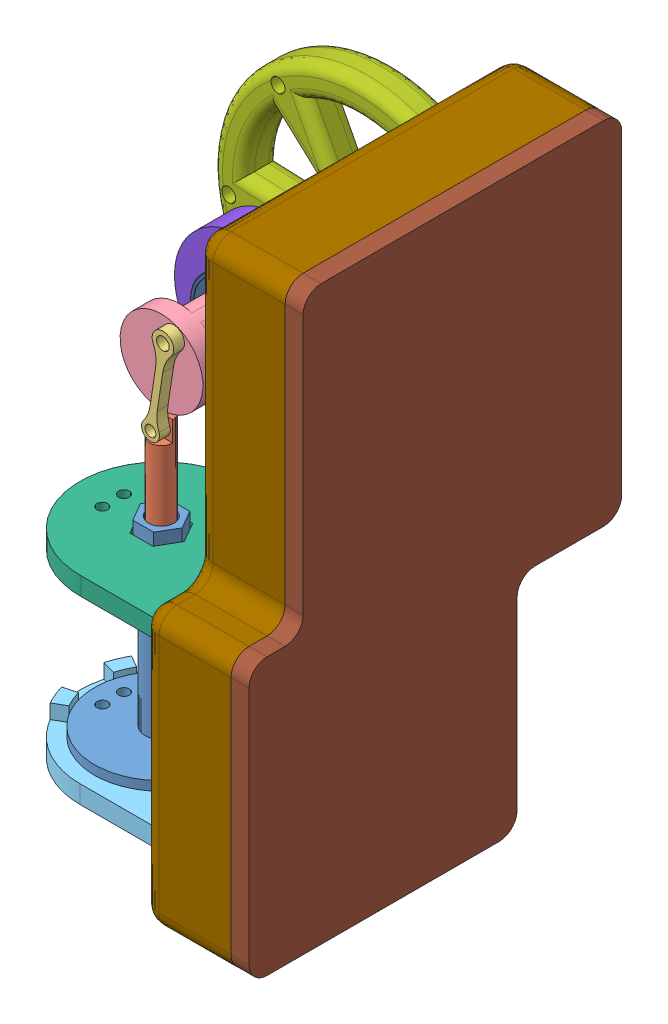
SolidWorks assembly 2pisengine, configuration Default. Lengths in mm.
Overall size (108.68 162.99 107.76).
15 component instances, 13 part files, 44 mates.
Components (placement in the parent):
- actuater-1: actuater [Default] at origin size (37.1 77.79 37.1) (flexible)
  - Spool_V1-1: Spool_V1 [Default] at (35.0022 -0.1462 27.5826) size (37.1 53.12 37.1)
  - rod2-1: rod2 [Default] at (35.0022 77.6418 27.5826) x (-1 0 0) z (0 -1 0) size (6.35 6.35 45.12)
- linkage-2: linkage [Default] at (38.4493 97.5834 30.5826) x (-0.149874 -0.988705 0) z (0.988705 -0.149874 0) size (28.5 3 6)
- pin-2: pin [Default] at (35.0022 74.8431 24.9704) x (0.997592 0.06936 0) z (0.06936 -0.997592 0) size (2.5 16 2.5) (hidden)
- spinner-1: spinner [Default] at (35.0682 90 -77.4174) x (0.407215 0.913332 0) z (0 0 1) size (23 23 64.21)
- base-1: base [Default] at (35.0022 -5.1462 27.5826) x (0 1 0) z (0 0 1) size (9 48.18 45.14)
- base2-1: base2 [Default] at (35.0022 49.9738 27.5826) x (0 -1 0) z (0.266317 0 0.963886) size (52.64 53.27 51.14)
- holder-2: holder [Default] at (35.0682 90 -36.6259) x (0 0 1) z (-0.462866 0.886428 0) size (10.59 80.54 80.54)
- holder2-1: holder2 [Default] at (35.0682 90 5.0146) x (0 0 -1) z (1 0 0) size (10 37.96 44.48)
- Part2-1: Part2 [Default] at (63.5682 -5.1462 50.1505) x (0 -1 0) z (1 0 0) size (158.81 103.42 25)
- 608RS-1: 608RS [Default] at (35.0682 90 -5.0854) x (0.988989 0.14799 0) z (0 0 1) size (22 22 7)
- 608RS-2: 608RS [Default] at (35.0682 90 1.7146) x (0.99964 0.026848 0) z (0 0 1) size (22 22 7)
- bottomlid-1: bottomlid [Default] at (114.8906 -3.1844 28.8479) x (0 -1 0) z (1 0 0)
- Part6^engine-1: Part6^engine [Default] at (83.5682 -5.1462 50.1505) x (0 -1 0) z (1 0 0) size (158.81 103.42 103.17)
Mates (geometry in assembly coordinates):
- Parallel2: parallel anti-aligned: plane of actuater-1/rod-1 through (35.0022 77.6418 27.5826) normal (0 0 1); plane of linkage-2 through (48.2867 89.0848 27.5826) normal (0 0 -1)
- Concentric2: concentric anti-aligned: circle of actuater-1/rod-1; circle of linkage-2
- Coincident5: coincident anti-aligned: plane of actuater-1/rod-1 through (35.0022 77.6418 27.5826) normal (0 0 1); plane of linkage-2 through (48.2867 89.0848 27.5826) normal (0 0 -1)
- Coincident10: coincident aligned: plane of actuater-1/rod-1 through (35.0022 77.6418 27.5826) normal (0 0 1); plane of spinner-1 through (35.0682 90 27.5826) normal (0 0 1)
- Perpendicular1: perpendicular: cylinder of actuater-1/Spool_V1-1 through (35.0022 22.4138 27.5826) axis (0 -1 0) radius 4.55; cylinder of spinner-1 through (35.0682 90 22.5826) axis (0 0 -1) radius 5
- Coincident20: coincident: point of spinner-1; plane of assembly
- Concentric6: concentric anti-aligned: cylinder of actuater-1/rod-1 through (35.0022 74.8431 20.5826) axis (0 0 1) radius 1.5; cylinder of pin-2 through (35.0022 74.8431 30.9704) axis (0 0 -1) radius 1.25
- Concentric10: concentric aligned: cylinder of linkage-2 through (38.4493 97.5834 27.5826) axis (0 0 1) radius 1.75; cylinder of spinner-1 through (38.4493 97.5834 -11.6259) axis (0 0 1) radius 1.5
- Coincident23: coincident anti-aligned: plane of actuater-1/Spool_V1-1 through (35.0022 -0.1462 27.5826) normal (0 -1 0); plane of base-1 through (35.0022 -0.1462 27.5826) normal (0 1 0)
- Coincident25: coincident: plane of actuater-1/Spool_V1-1 through (35.0022 44.9738 27.5826) normal (0 1 0); plane of base2-1 through (35.0022 44.9738 27.5826) normal (0 -1 0)
- Concentric13: concentric aligned: circle of actuater-1/Spool_V1-1; circle of base-1
- Parallel5: parallel anti-aligned: line of base2-1 through (58.5682 44.9738 45.1005) axis (0 -1 0); line of basebot-1 through (58.5682 -0.0962 50.1505) axis (0 1 0)
- Parallel6: parallel aligned: line of base2-1 through (58.5682 44.9738 10.0646) axis (0 -1 0); line of basebot-1 through (58.5682 44.9238 5.0146) axis (0 -1 0)
- Parallel7: parallel anti-aligned: plane of base2-1 through (58.5682 81.778 10.0646) normal (1 0 0); plane of basebot-1 through (58.5682 -5.1462 50.1505) normal (-1 0 0)
- Coincident32: coincident anti-aligned: plane of base2-1 through (58.5682 81.778 10.0646) normal (1 0 0); plane of basebot-1 through (58.5682 -5.1462 50.1505) normal (-1 0 0)
- Coincident35: coincident aligned: plane of base-1 through (60.6182 -5.1462 5.0146) normal (0 0 -1); plane of basebot-1 through (58.5682 -5.1462 5.0146) normal (0 0 -1)
- Parallel12: parallel aligned: cylinder of spinner-1 through (35.0682 90 22.5826) axis (0 0 -1) radius 5; line of basebot-1 through (58.5682 108.9805 50.1505) axis (0 0 -1)
- Parallel15: parallel anti-aligned: plane of spinner-1 through (35.0682 90 14.5826) normal (0 0 -1); plane of holder-2 through (35.0682 90 -26.6259) normal (0 0 1)
- Concentric14: concentric aligned: cylinder of spinner-1 through (35.0682 90 13.3741) axis (0 0 -1) radius 4.025; cylinder of holder-2 through (35.0682 90 -26.6259) axis (0 0 -1) radius 4.025
- Coincident43: coincident anti-aligned: plane of spinner-1 through (37.2843 91.1572 -26.6259) normal (0.886428 0.462866 0); plane of holder-2 through (37.2843 91.1572 -26.6259) normal (-0.886428 -0.462866 0)
- Coincident46: coincident anti-aligned: plane of spinner-1 through (35.0682 90 -26.6259) normal (0 0 -1); plane of holder-2 through (35.0682 90 -26.6259) normal (0 0 1)
- Parallel17: parallel anti-aligned: plane of spinner-1 through (35.0682 90 14.5826) normal (0 0 -1); plane of holder2-1 through (35.0682 90 5.0146) normal (0 0 1)
- Concentric15: concentric anti-aligned: cylinder of spinner-1 through (35.0682 90 13.3741) axis (0 0 -1) radius 4.025; cylinder of holder2-1 through (35.0682 90 -4.9854) axis (0 0 1) radius 18.9805
- Coincident49: coincident: point of spinner-1; plane of assembly
- Parallel18: parallel aligned: plane of base2-1 through (35.0022 49.9738 27.5826) normal (0 1 0); plane of holder2-1 through (58.5682 108.9805 -4.9854) normal (0 1 0)
- Coincident51: coincident anti-aligned: line of basebot-1 through (58.5682 71.0195 5.0146) axis (1 0 0); line of holder2-1 through (60.5682 71.0195 5.0146) axis (-1 0 0)
- InPlace1: in place: plane of ? through (63.3682 -5.1462 50.1505) normal (1 0 0); plane of ? through (63.3682 0 0) normal (1 0 0); moOrthogonalPlaneRef_w of ? through (63.3682 -5.1462 50.1505) normal (1 0 0); plane of ? through (63.3682 0 0) normal (0 1 0); plane of ? through (63.3682 -5.1462 50.1505) normal (1 0 0); plane of ? through (63.3682 0 0) normal (0 0 -1); plane of ? through (63.5682 -5.1462 50.1505) normal (1 0 0); unknown of Part2-1
- Coincident52: coincident aligned: plane of ?; plane of Part2-1
- Coincident53: coincident aligned: moOrthogonalPlaneRef_w of basebot-1 through (63.5682 -5.1462 50.1505) normal (0 0 -1); plane of Part2-1 through (63.5682 -5.1462 50.1505) normal (0 0 -1)
- Coincident54: coincident anti-aligned: moOrthogonalPlaneRef_w of basebot-1 through (63.5682 -5.1462 50.1505) normal (0 1 0); plane of Part2-1 through (63.5682 -5.1462 50.1505) normal (0 -1 0)
- Coincident52: coincident anti-aligned: circle of holder2-1; cylinder of 608RS-1 through (35.0682 90 1.9146) axis (0 0 -1) radius 11
- Coincident53: coincident aligned: plane of holder2-1 through (35.0682 90 -4.9854) normal (0 0 -1); plane of 608RS-1 through (35.0682 90 -4.9854) normal (0 0 -1)
- Concentric16: concentric anti-aligned: cylinder of holder2-1 through (35.0682 90 -4.9854) axis (0 0 1) radius 11; cylinder of 608RS-2 through (35.0682 90 8.7146) axis (0 0 -1) radius 11
- Coincident54: coincident anti-aligned: plane of 608RS-1 through (35.0682 90 1.8146) normal (0 0 1); plane of 608RS-2 through (35.0682 90 1.8146) normal (0 0 -1)
- InPlace3: in place: plane of ? through (58.3682 -5.1462 50.1505) normal (-1 0 0); plane of ? through (58.3682 0 0) normal (-1 0 0); plane of ? through (58.3682 -5.1462 50.1505) normal (-1 0 0); plane of ? through (58.3682 0 0) normal (0 1 0); plane of ? through (58.3682 -5.1462 50.1505) normal (-1 0 0); plane of ? through (58.3682 0 0) normal (0 0 1); plane of Part2-1 through (58.5682 -5.1462 50.1505) normal (-1 0 0); unknown of ?
- Coincident58: coincident aligned: plane of Part2-1; plane of ?
- Coincident59: coincident aligned: moOrthogonalPlaneRef_w of Part2-1 through (58.5682 -5.1462 50.1505) normal (0 0 -1); plane of Part5^engine-1 through (58.3682 -5.1462 50.1505) normal (0 0 -1)
- Coincident60: coincident anti-aligned: moOrthogonalPlaneRef_w of Part2-1 through (58.5682 -5.1462 50.1505) normal (0 -1 0); plane of Part5^engine-1 through (58.3682 -5.1462 50.1505) normal (0 1 0)
- Concentric17: concentric: circle of actuater-1/Spool_V1-1; circle of base2-1
- LimitDistance1: limit distance = 27.6679 mm aligned: plane of actuater-1/rod-1 through (35.0022 77.6418 27.5826) normal (0 1 0); plane of base2-1 through (35.0022 49.9738 27.5826) normal (0 1 0)
- InPlace4: in place: plane of Part2-1 through (83.5682 -5.1462 50.1505) normal (1 0 0); plane of ? through (83.5682 0 0) normal (1 0 0); plane of Part2-1 through (83.5682 -5.1462 50.1505) normal (1 0 0); plane of ? through (83.5682 0 0) normal (0 1 0); plane of Part2-1 through (83.5682 -5.1462 50.1505) normal (1 0 0); plane of ? through (83.5682 0 0) normal (0 0 -1); plane of Part2-1 through (83.5682 -5.1462 50.1505) normal (1 0 0); unknown of Part6^engine-1
- Coincident57: coincident aligned: plane of Part2-1; plane of Part6^engine-1
- Coincident58: coincident aligned: moOrthogonalPlaneRef_w of Part2-1 through (83.5682 -5.1462 50.1505) normal (0 0 -1); plane of Part6^engine-1 through (83.5682 -5.1462 50.1505) normal (0 0 -1)
- Coincident59: coincident anti-aligned: moOrthogonalPlaneRef_w of Part2-1 through (83.5682 -5.1462 50.1505) normal (0 1 0); plane of Part6^engine-1 through (83.5682 -5.1462 50.1505) normal (0 -1 0)
